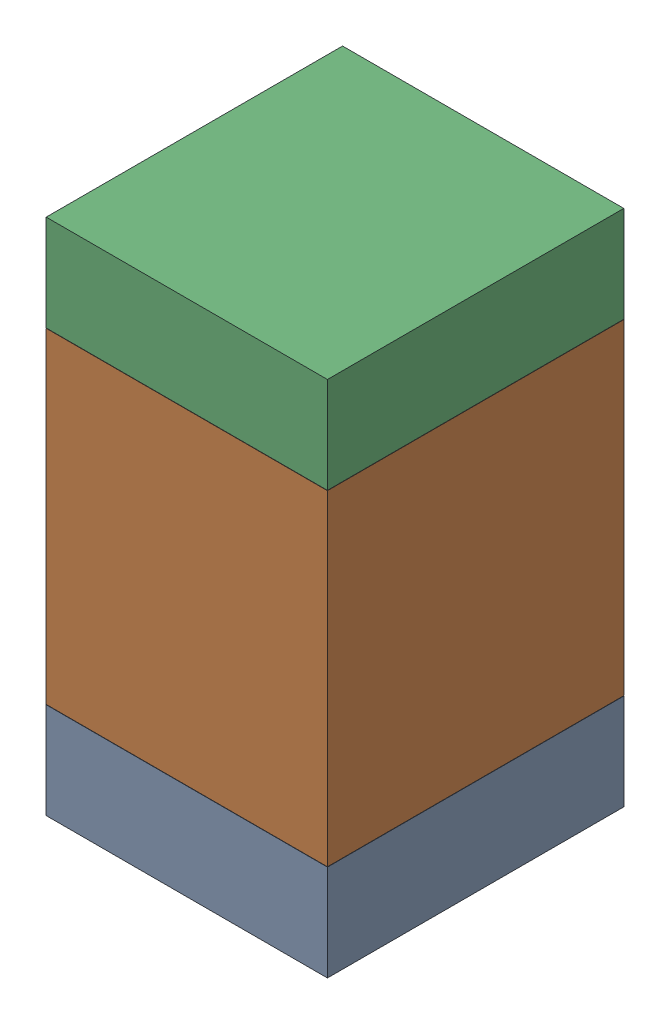
SolidWorks assembly R2, configuration Default. Lengths in mm.
Overall size (0.95 1.75 1).
6 component instances, 2 part files, 0 mates.
Components (placement in the parent):
- 6575495072-1: 6575495072 [Default] at (2.286 42.5945 0) size (0.95 0.32 1)
  - Extruded_6-1: Extruded_6 [Default] at origin size (0.95 0.32 1)
- 6575494912-1: 6575494912 [Default] at (2.286 43.307 0) size (0.95 1.1 1)
  - Extruded_7-1: Extruded_7 [Default] at origin size (0.95 1.1 1)
- 6575495072-2: 6575495072 [Default] at (2.286 44.0195 0) size (0.95 0.32 1)
  - Extruded_6-1: Extruded_6 [Default] at origin size (0.95 0.32 1)
